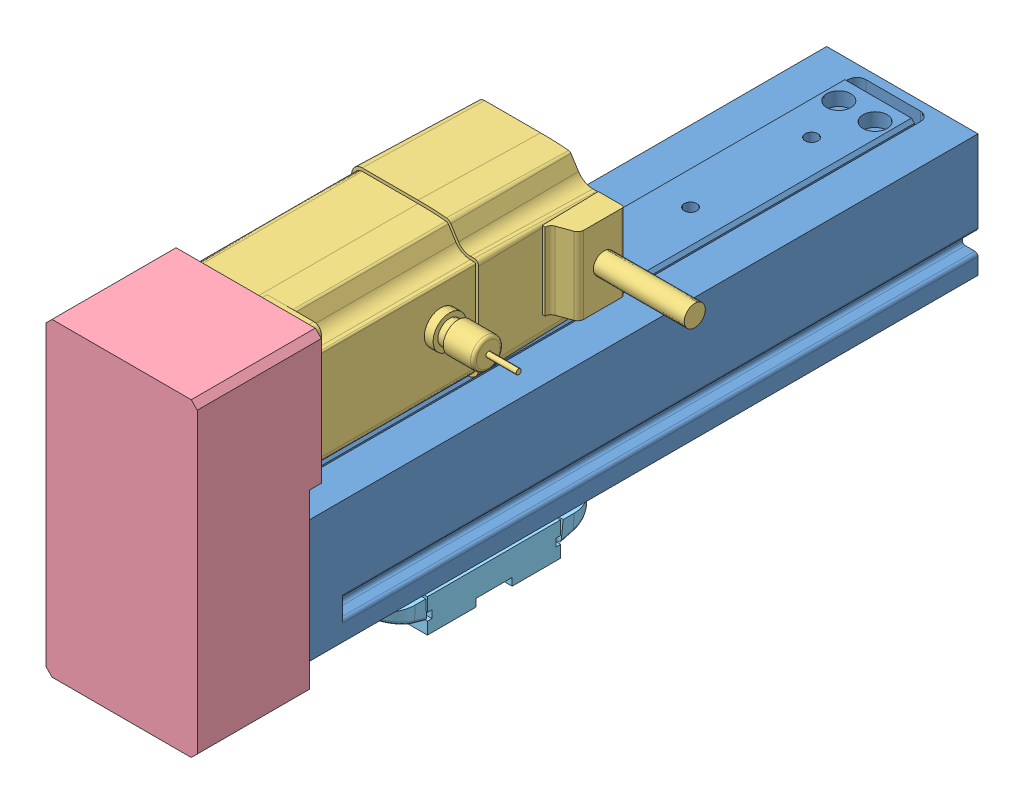
SolidWorks assembly S5M-BM-100W, configuration 默认. Lengths in mm.
Overall size (97.2 104.4 258).
7 component instances, 5 part files, 22 mates.
Components (placement in the parent):
- S5-BL-导轨^S5M-BM-100W-1: S5-BL-导轨^S5M-BM-100W [默认] x (-1 0 0) z (0 0 -1) size (50 42.7 221) (virtual)
- 传感器^S5M-BM-100W-3: 传感器^S5M-BM-100W [默认] at (-31.75 -24.6 -163) x (-1 0 0) z (0 0 -1) size (13.5 27.2 26.1) (virtual)
- 传感器^S5M-BM-100W-5: 传感器^S5M-BM-100W [默认] at (-31.75 -24.6 -45) x (-1 0 0) z (0 0 -1) size (13.5 27.2 26.1) (virtual)
- 传感器^S5M-BM-100W-6: 传感器^S5M-BM-100W [默认] at (-31.75 -24.6 -71.1) x (-1 0 0) z (0 0 -1) size (13.5 27.2 26.1) (virtual)
- 100W 电机^S5M-BM-100W-1: 100W 电机^S5M-BM-100W [默认] at (0 35.5 -59) x (0 -1 0) z (0 0 -1) size (42.54 79.97 121.5) (virtual)
- S5-BM-P10电机安装板^S5M-BM-100W-1: S5-BM-P10电机安装板^S5M-BM-100W [默认] at (0 -30.0332 1) x (0 -1 0) z (-1 0 0) size (102.4 41 50) (virtual)
- S5-BC-滑块组件^S5M-BM-100W-1: S5-BC-滑块组件^S5M-BM-100W [Default] at (-16.8713 -4.7727 -106.049) x (-1 0 0) z (0 0 1) size (57.33 40 73.16) (virtual)
Mates (geometry in assembly coordinates):
- 重合144: coincident: plane of 传感器^S5M-BM-100W-3 through (-25 -35.7 -169.3) normal (0 -1 0); plane of 传感器^S5M-BM-100W-6 through (-25 -35.7 -77.4) normal (0 -1 0)
- 重合148: coincident: plane of 传感器^S5M-BM-100W-6 through (-25 -35.7 -77.4) normal (0 -1 0); plane of 传感器^S5M-BM-100W-5 through (-25 -35.7 -51.3) normal (0 -1 0)
- 距离28: distance = 19.8 mm: plane of 传感器^S5M-BM-100W-6 through (-38.5 -13.5 -71.1) normal (0 0 1); plane of 传感器^S5M-BM-100W-5 through (-38.5 -13.5 -51.3) normal (0 0 -1)
- 距离29: distance = 25 mm: plane of S5-BC-滑块组件^S5M-BM-100W-1; plane of S5-BL-导轨^S5M-BM-100W-1 through (-25 7 -10) normal (-1 0 0)
- 距离30: distance = 54 mm: plane of S5-BC-滑块组件^S5M-BM-100W-1 through (-21 -45.5 -74.049) normal (0 -1 0); plane of S5-BL-导轨^S5M-BM-100W-1 through (12 8.5 -212) normal (0 1 0)
- 重合188: coincident: plane of 传感器^S5M-BM-100W-3 through (-25 -35.7 -169.3) normal (1 0 0); plane of 传感器^S5M-BM-100W-5 through (-25 -35.7 -51.3) normal (1 0 0)
- 重合189: coincident: plane of 传感器^S5M-BM-100W-5 through (-25 -35.7 -51.3) normal (1 0 0); plane of 传感器^S5M-BM-100W-6 through (-25 -35.7 -77.4) normal (1 0 0)
- 重合190: coincident: plane of 传感器^S5M-BM-100W-5 through (-25 -13.5 -51.3) normal (0 1 0); plane of 传感器^S5M-BM-100W-6 through (-25 -13.5 -77.4) normal (0 1 0)
- 重合191: coincident: plane of 传感器^S5M-BM-100W-3 through (-25 -13.5 -169.3) normal (0 1 0); plane of 传感器^S5M-BM-100W-6 through (-25 -13.5 -77.4) normal (0 1 0)
- 重合192: coincident: plane of 传感器^S5M-BM-100W-3 through (-25 -35.7 -169.3) normal (1 0 0); plane of S5-BL-导轨^S5M-BM-100W-1 through (-25 7 -10) normal (-1 0 0)
- 距离35: distance = 22 mm: plane of 传感器^S5M-BM-100W-3 through (-25 -13.5 -169.3) normal (0 1 0); plane of S5-BL-导轨^S5M-BM-100W-1 through (12 8.5 -212) normal (0 1 0)
- 距离37: distance = 40.8 mm: plane of 传感器^S5M-BM-100W-3 through (-28 -16.7 -179.2) normal (0 0 -1); plane of S5-BL-导轨^S5M-BM-100W-1 through (0 0 -220) normal (0 0 -1)
- 重合193: coincident: plane of S5-BL-导轨^S5M-BM-100W-1 through (0 0 1) normal (0 0 1); plane of S5-BM-P10电机安装板^S5M-BM-100W-1 through (-25 -43.5 1) normal (0 0 -1)
- 重合194: coincident: plane of S5-BL-导轨^S5M-BM-100W-1 through (-25 7 -10) normal (-1 0 0); plane of S5-BM-P10电机安装板^S5M-BM-100W-1 through (-25 -30.0332 1) normal (-1 0 0)
- 距离40: distance = 9.3 mm: plane of S5-BL-导轨^S5M-BM-100W-1 through (-12.5 -34.2 -8) normal (0 -1 0); plane of S5-BM-P10电机安装板^S5M-BM-100W-1 through (-25 -43.5 9) normal (0 -1 0)
- 重合196: coincident: plane of 100W 电机^S5M-BM-100W-1 through (0.0086 35.5197 -3) normal (0 0 1); plane of S5-BM-P10电机安装板^S5M-BM-100W-1 through (-25 15.5 -3) normal (0 0 -1)
- 同心1: concentric: cylinder of 100W 电机^S5M-BM-100W-1 through (0 35.5 -3) axis (0 0 1) radius 4; cylinder of S5-BM-P10电机安装板^S5M-BM-100W-1 through (0 35.5 -3) axis (0 0 1) radius 8
- 平行1: parallel: plane of 100W 电机^S5M-BM-100W-1 through (17.5 15.5 -59) normal (0 -1 0); plane of S5-BM-P10电机安装板^S5M-BM-100W-1 through (-25 15.5 1) normal (0 -1 0)
- 距离41: distance = 73.1 mm: plane of 传感器^S5M-BM-100W-5 through (-28 -16.7 -35.1) normal (0 0 1); plane of S5-BM-P10电机安装板^S5M-BM-100W-1 through (0 -30.0332 38) normal (0 0 1)
- 重合197: coincident: plane of S5-BL-导轨^S5M-BM-100W-1 through (0 0 0) normal (-1 0 0); plane of assembly through (0 0 0) normal (1 0 0)
- 重合198: coincident: plane of S5-BL-导轨^S5M-BM-100W-1; plane of assembly through (0 0 0) normal (0 1 0)
- 重合199: coincident: plane of S5-BL-导轨^S5M-BM-100W-1 through (0 0 0) normal (0 0 -1); plane of assembly through (0 0 0) normal (0 0 1)
